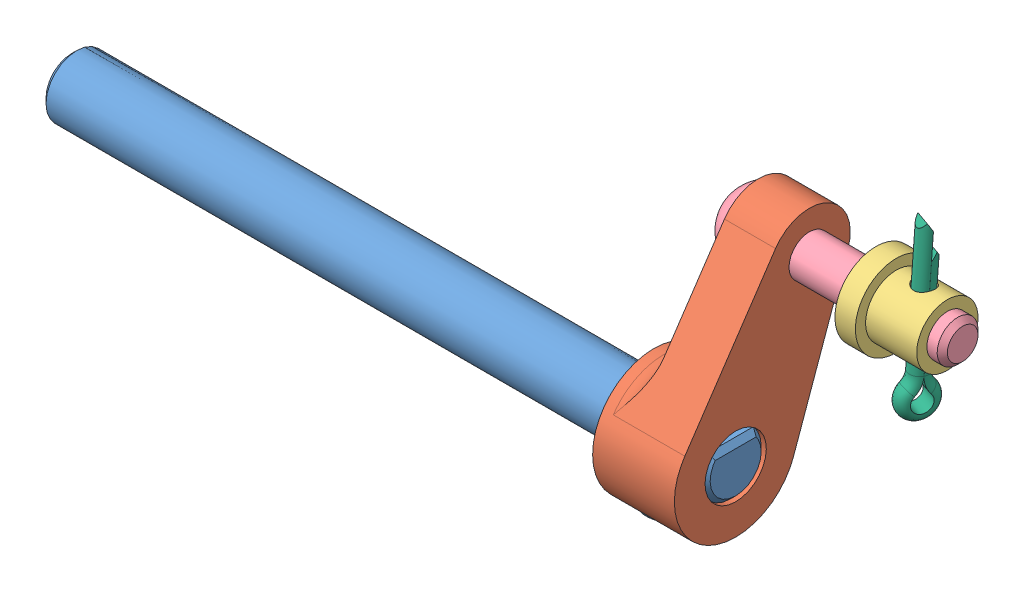
SolidWorks assembly 47.sub assembly crankshaft, configuration Default. Lengths in mm.
Overall size (83.74 74.17 48.73).
6 component instances, 6 part files, 10 mates.
Components (placement in the parent):
- 37.crankshaft rod-1: 37.crankshaft rod [Default] at (23.2641 33.8463 50.4705) size (65 6 6)
- 36.crankshaft roker-1: 36.crankshaft roker [Default] at (55.7641 33.8463 50.4705) x (0 -0.451163 -0.892442) z (0 0.892442 -0.451163) size (13.08 8 26)
- 38.crankshaft nut-1: 38.crankshaft nut [Default] at (65.7641 48.1254 43.2519) x (1 0 0) z (0 0.07788 0.996963) size (7 8 8)
- 39.crankshaft bolt-1: 39.crankshaft bolt [Default] at (50.7641 48.1254 43.2519) x (-1 0 0) z (0 0.996963 -0.07788) size (22.76 7 7)
- socket set screw flat point_din-1: socket set screw flat point_din [PreviewCfg] at (50.7641 28.4917 53.1774) x (0 0.892442 -0.451163) z (-0.966918 0.115086 0.227652) size (50 24 24)
- split pin_din-1: split pin_din [PreviewCfg] at (66.7641 44.0832 43.5676) x (0 0.996963 -0.07788) z (-0.938495 -0.026891 -0.344244) size (71.3 19 9.5)
Mates (geometry in assembly coordinates):
- Concentric4: concentric anti-aligned: cylinder of 38.crankshaft nut-1 through (62.2641 48.1254 43.2519) axis (1 0 0) radius 2; cylinder of 39.crankshaft bolt-1 through (70.7641 48.1254 43.2519) axis (-1 0 0) radius 2
- Concentric5: concentric aligned: cylinder of 38.crankshaft nut-1 through (66.7641 44.1375 43.5634) axis (0 0.996963 -0.07788) radius 1; cylinder of 39.crankshaft bolt-1 through (66.7641 46.1315 43.4076) axis (0 0.996963 -0.07788) radius 1
- Concentric7: concentric aligned: cylinder of 36.crankshaft roker-1 through (50.7641 26.537 54.1656) axis (0 -0.892442 0.451163) radius 1.5; cylinder of socket set screw flat point_din-1 through (50.7641 17.1577 58.9072) axis (0 -0.892442 0.451163) radius 12
- Tangent1: tangent aligned: cylinder of 36.crankshaft roker-1 through (50.7641 33.8463 50.4705) axis (1 0 0) radius 6; plane of socket set screw flat point_din-1 through (50.7641 28.4917 53.1774) normal (0 -0.892442 0.451163)
- Concentric8: concentric aligned: cylinder of 38.crankshaft nut-1 through (66.7641 44.1375 43.5634) axis (0 0.996963 -0.07788) radius 1; cylinder of split pin_din-1 through (66.7641 44.0832 43.5676) axis (0 0.996963 -0.07788) radius 4.75
- Lock1: lock: unknown of 38.crankshaft nut-1; unknown of split pin_din-1
- Concentric9: concentric aligned: cylinder of 37.crankshaft rod-1 through (55.7641 33.8463 50.4705) axis (-1 0 0) radius 3; cylinder of 36.crankshaft roker-1 through (55.7641 33.8463 50.4705) axis (-1 0 0) radius 3
- Coincident5: coincident aligned: plane of 37.crankshaft rod-1 through (55.7641 33.8463 50.4705) normal (1 0 0); plane of 36.crankshaft roker-1 through (55.7641 33.8463 50.4705) normal (1 0 0)
- Concentric10: concentric anti-aligned: cylinder of 36.crankshaft roker-1 through (50.7641 48.1254 43.2519) axis (1 0 0) radius 2; cylinder of 39.crankshaft bolt-1 through (70.7641 48.1254 43.2519) axis (-1 0 0) radius 2
- Coincident6: coincident anti-aligned: plane of 36.crankshaft roker-1 through (50.7641 33.8463 50.4705) normal (-1 0 0); plane of 39.crankshaft bolt-1 through (50.7641 48.1254 43.2519) normal (1 0 0)
